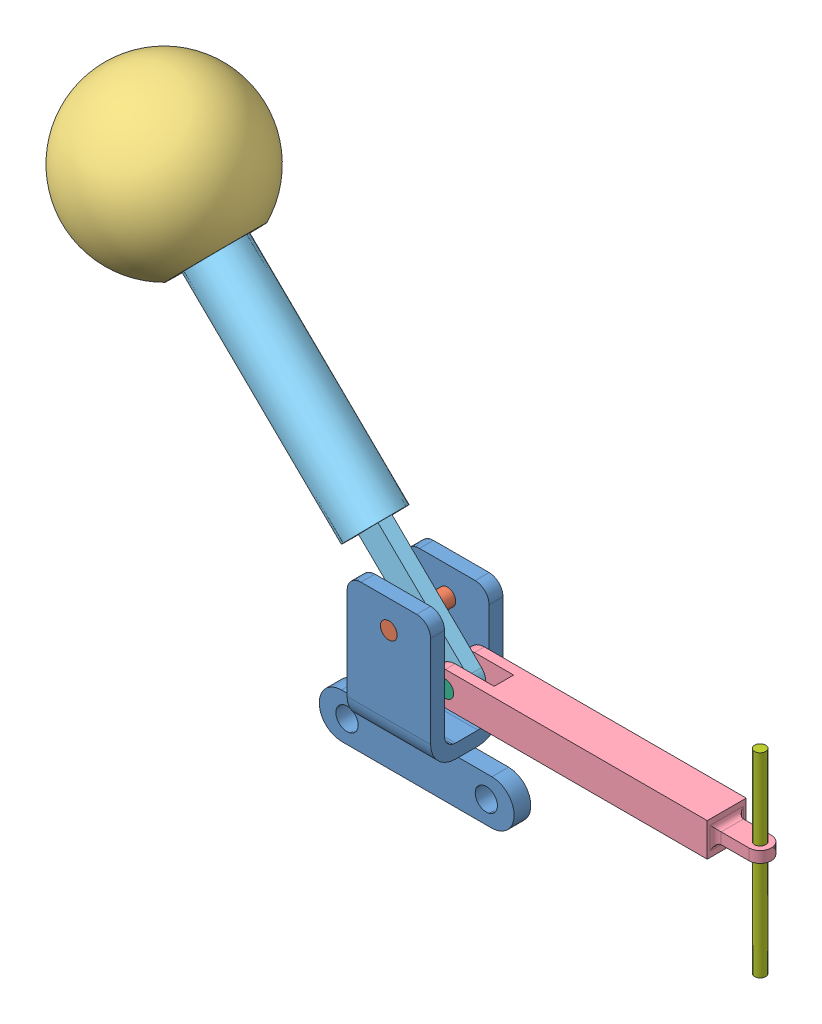
SolidWorks assembly Upper_Assembly, configuration Default. Lengths in mm.
Overall size (283.61 192.18 74.45).
7 component instances, 7 part files, 13 mates.
Components (placement in the parent):
- Box_Pivot-1: Box_Pivot [Default] at (11.9261 53.6915 54.2812) size (70 63 26)
- Big Post-1: Big Post [Default] at (11.9261 68.2515 41.2812) x (0.772904 -0.634523 0) z (0 0 1) size (6 6 26)
- Handle-1: Handle [Default] at (-81.7306 159.8453 54.2812) x (-0.196514 -0.20094 -0.95969) z (0.671005 0.686118 -0.28106) size (60 56 60)
- Link-1: Link [Default] at (120.2249 54.2677 54.2812) size (134.18 12 14)
- Post Handle-1: Post Handle [Default] at (-34.5447 113.6988 54.2812) x (-0.714937 0.699189 0) z (0 0 1) size (140 20 20)
- Small Post-1: Small Post [Default] at (26.2249 54.2677 47.2812) x (0.979703 -0.200456 0) z (0 0 1) size (6 6 14)
- Long Rod-1: Long Rod [Default] at (132.2249 15.2515 54.2812) x (0.987298 0 0.158876) z (-0.158876 0 0.987298) size (4 70 4)
Mates (geometry in assembly coordinates):
- Concentric1: concentric anti-aligned: cylinder of Box_Pivot-1 through (11.9261 68.2515 41.2812) axis (0 0 1) radius 3; cylinder of Big Post-1 through (11.9261 68.2515 67.2812) axis (0 0 -1) radius 3
- Coincident1: coincident aligned: plane of Box_Pivot-1 through (26.9261 78.2515 67.2812) normal (0 0 1); plane of Big Post-1 through (11.9261 68.2515 67.2812) normal (0 0 1)
- Concentric2: concentric aligned: cylinder of Big Post-1 through (11.9261 68.2515 67.2812) axis (0 0 -1) radius 3; cylinder of Post Handle-1 through (11.9261 68.2515 56.7812) axis (0 0 -1) radius 3
- Width1: width anti-aligned: plane of Box_Pivot-1 through (26.9261 40.2515 46.2812) normal (0 0 1); plane of Box_Pivot-1 through (26.9261 78.2515 62.2812) normal (0 0 -1); plane of Post Handle-1 through (26.2249 54.2677 51.7812) normal (0 0 -1); plane of Post Handle-1 through (26.2249 54.2677 56.7812) normal (0 0 1)
- Concentric3: concentric aligned: cylinder of Handle-1 through (-71.7214 150.0566 54.2812) axis (0.714937 -0.699189 0) radius 6; cylinder of Post Handle-1 through (-70.2916 148.6583 54.2812) axis (0.714937 -0.699189 0) radius 6
- Coincident3: coincident anti-aligned: plane of Handle-1 through (-63.1422 141.6664 54.2812) normal (0.714937 -0.699189 0); plane of Post Handle-1 through (-63.1422 141.6664 54.2812) normal (-0.714937 0.699189 0)
- Concentric4: concentric aligned: cylinder of Link-1 through (26.2249 54.2677 61.2812) axis (0 0 -1) radius 3; cylinder of Post Handle-1 through (26.2249 54.2677 56.7812) axis (0 0 -1) radius 3
- Width2: width anti-aligned: plane of Link-1 through (20.2249 48.2677 50.7812) normal (0 0 1); plane of Link-1 through (40.2249 48.2677 57.7812) normal (0 0 -1); plane of Post Handle-1 through (26.2249 54.2677 51.7812) normal (0 0 -1); plane of Post Handle-1 through (26.2249 54.2677 56.7812) normal (0 0 1)
- Concentric5: concentric aligned: cylinder of Post Handle-1 through (26.2249 54.2677 56.7812) axis (0 0 -1) radius 3; cylinder of Small Post-1 through (26.2249 54.2677 61.2812) axis (0 0 -1) radius 3
- Width3: width anti-aligned: plane of Small Post-1 through (26.2249 54.2677 61.2812) normal (0 0 1); plane of Small Post-1 through (26.2249 54.2677 47.2812) normal (0 0 -1); plane of Link-1 through (26.2249 54.2677 47.2812) normal (0 0 -1); plane of Link-1 through (26.2249 54.2677 61.2812) normal (0 0 1)
- Parallel1: parallel aligned: plane of Box_Pivot-1 through (26.9261 36.2515 58.2812) normal (0 1 0); plane of Link-1 through (120.2249 60.2677 61.2812) normal (0 1 0)
- Coincident4: coincident aligned: plane of Box_Pivot-1 through (-15.0739 15.2515 57.2812) normal (0 -1 0); plane of Long Rod-1 through (132.2249 15.2515 54.2812) normal (0 -1 0)
- Concentric6: concentric aligned: cylinder of Link-1 through (132.2249 60.2677 54.2812) axis (0 -1 0) radius 2; cylinder of Long Rod-1 through (132.2249 85.2515 54.2812) axis (0 -1 0) radius 2
